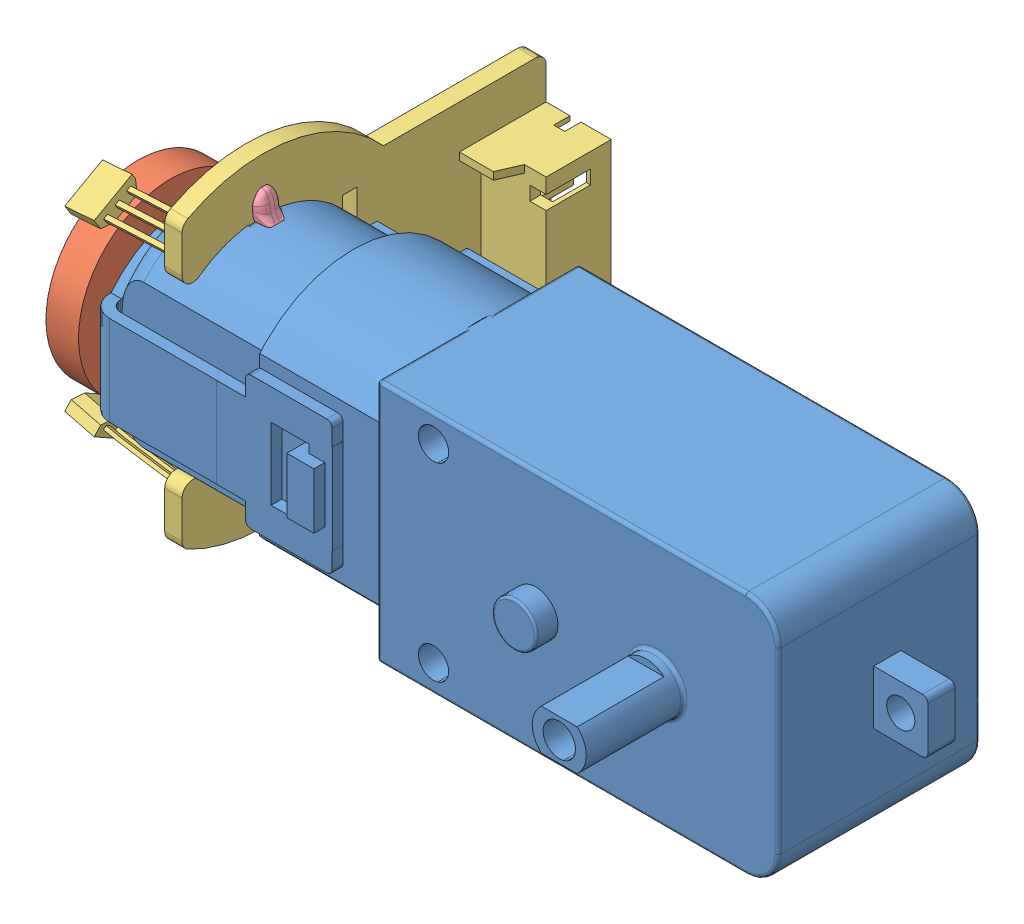
SolidWorks assembly Assem1, configuration Default. Lengths in mm.
Overall size (73.48 29.86 44.39).
6 component instances, 4 part files, 0 mates.
Components (placement in the parent):
- FIT0450 v11.step-1: FIT0450 v11.step [Default] at origin size (73.48 29.86 44.39)
  - MainMotor.step-1: MainMotor.step [Default] at (-75.3959 -81.4996 -19.2021) x (0 1 0) z (-1 0 0) size (22.6 29.93 73.35)
  - EncoderDisc.step-1: EncoderDisc.step [Default] at (-140.7459 -89.424 -31.5975) x (0 1 0) z (-1 0 0) size (17 17 3)
  - EncoderPCB.step-1: EncoderPCB.step [Default] at (-132.1949 -89.549 -31.5975) x (0 -1 0) z (-1 0 0) size (29.86 33.59 17.68)
  - EncoderHolder.step-1: EncoderHolder.step [Default] at (-44.9961 -114.5071 5.3229) x (0 1 0) z (-1 0 0) size (3.24 2.01 2.38)
  - EncoderHolder.step-2: EncoderHolder.step [Default] at (-44.9961 -64.3409 -68.5341) x (0 -1 0) z (-1 0 0) size (3.24 2.01 2.38)
